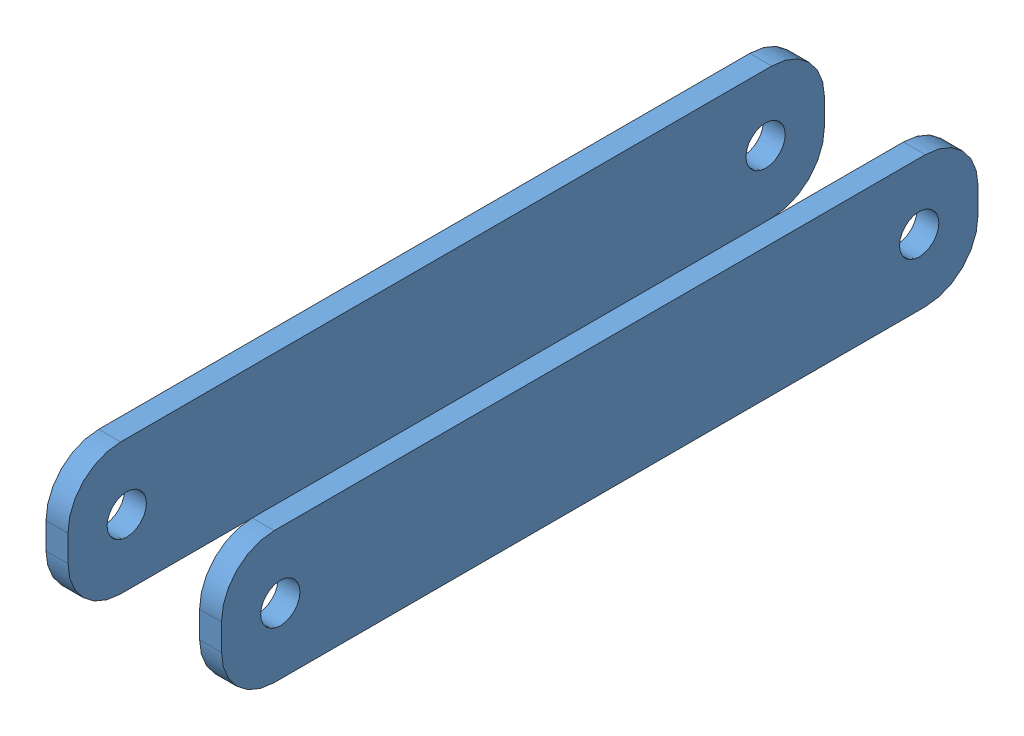
SolidWorks assembly r_gripper_fwd_link, configuration Default. Lengths in mm.
Overall size (12.7 9.53 54.74).
2 component instances, 1 part files, 4 mates.
Components (placement in the parent):
- gripper_link_forward-1: gripper_link_forward [Default] at (-1.5875 4.7625 -4.2545) x (0 0 1) z (0 1 0) size (54.74 1.59 9.53)
- gripper_link_forward-2: gripper_link_forward [Default] at (-12.7 4.7625 -4.2545) x (0 0 1) z (0 1 0) size (54.74 1.59 9.53)
Mates (geometry in assembly coordinates):
- Coincident2: coordinate: point of gripper_link_forward-1; point of assembly
- Concentric2: concentric: cylinder of gripper_link_forward-1 through (-1.5875 0 46.228) axis (1 0 0) radius 1.4224; cylinder of gripper_link_forward-2 through (-12.7 0 46.228) axis (1 0 0) radius 1.4224
- Distance2: distance = 12.7 mm: plane of gripper_link_forward-1 through (0 -4.7625 -4.2545) normal (1 0 0); plane of gripper_link_forward-2 through (-12.7 -4.7625 -4.2545) normal (-1 0 0)
- Concentric3: concentric aligned: cylinder of gripper_link_forward-1 through (-1.5875 0 0) axis (1 0 0) radius 1.4224; cylinder of gripper_link_forward-2 through (-12.7 0 0) axis (1 0 0) radius 1.4224
